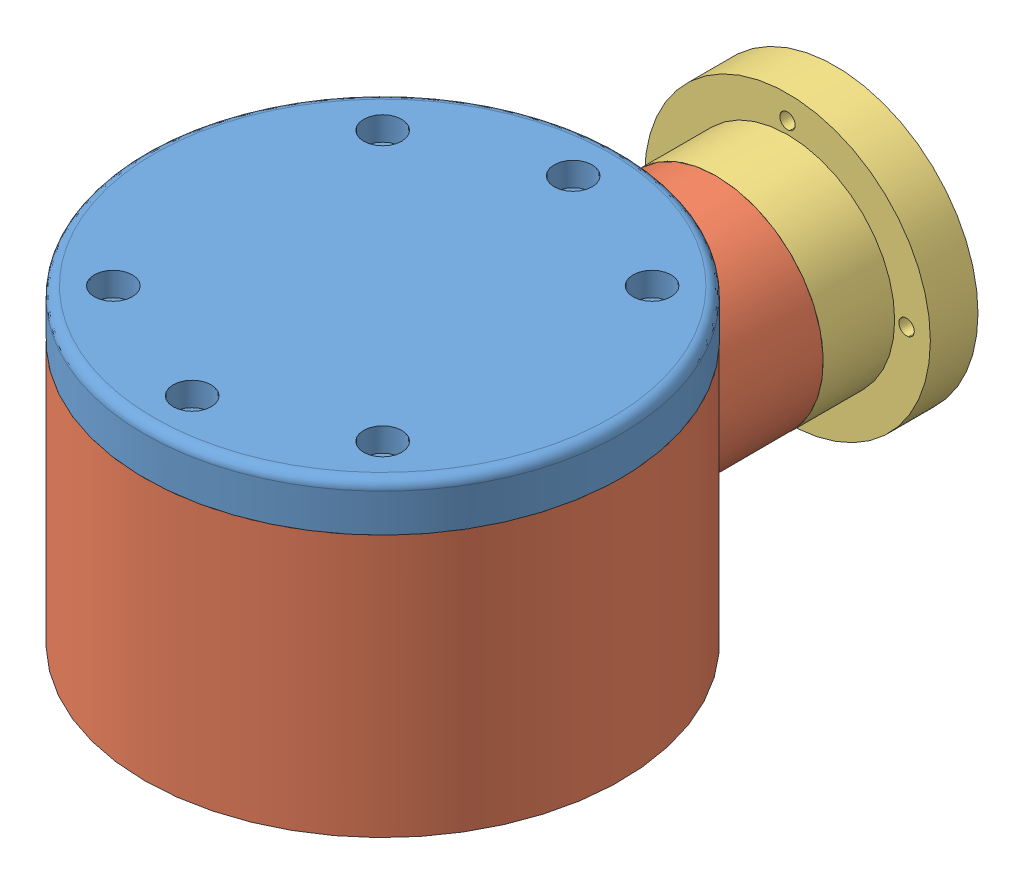
SolidWorks assembly [K4]Assembly, configuration Default. Lengths in mm.
Overall size (100 67.5 145).
3 component instances, 3 part files, 5 mates.
Components (placement in the parent):
- [K4]Nắp.stp-1: [K4]Nắp.stp [Default] at (14.6094 51.0377 86.1293) size (100 10 100)
- [K4]Thân.stp-1: [K4]Thân.stp [Default] at (14.6094 23.5377 86.1293) x (0 0 -1) z (1 0 0) size (120 55 100)
- [K4]Trục.stp-1: [K4]Trục.stp [Default] at (14.6094 23.5377 -8.8707) x (1 0 0) z (0 -1 0) size (60 75 60)
Mates (geometry in assembly coordinates):
- Coincident2: coincident anti-aligned: plane of [K4]Nắp.stp-1 through (14.6094 51.0377 86.1293) normal (0 -1 0); plane of [K4]Thân.stp-1 through (14.6094 51.0377 86.1293) normal (0 1 0)
- Concentric1: concentric anti-aligned: circle of [K4]Nắp.stp-1; circle of [K4]Thân.stp-1
- Concentric2: concentric anti-aligned: circle of [K4]Nắp.stp-1; circle of [K4]Thân.stp-1
- Coincident3: coincident anti-aligned: plane of [K4]Thân.stp-1 through (14.6094 23.5377 16.1293) normal (0 0 -1); plane of [K4]Trục.stp-1 through (14.6094 23.5377 16.1293) normal (0 0 1)
- Concentric3: concentric aligned: circle of [K4]Thân.stp-1; circle of [K4]Trục.stp-1
